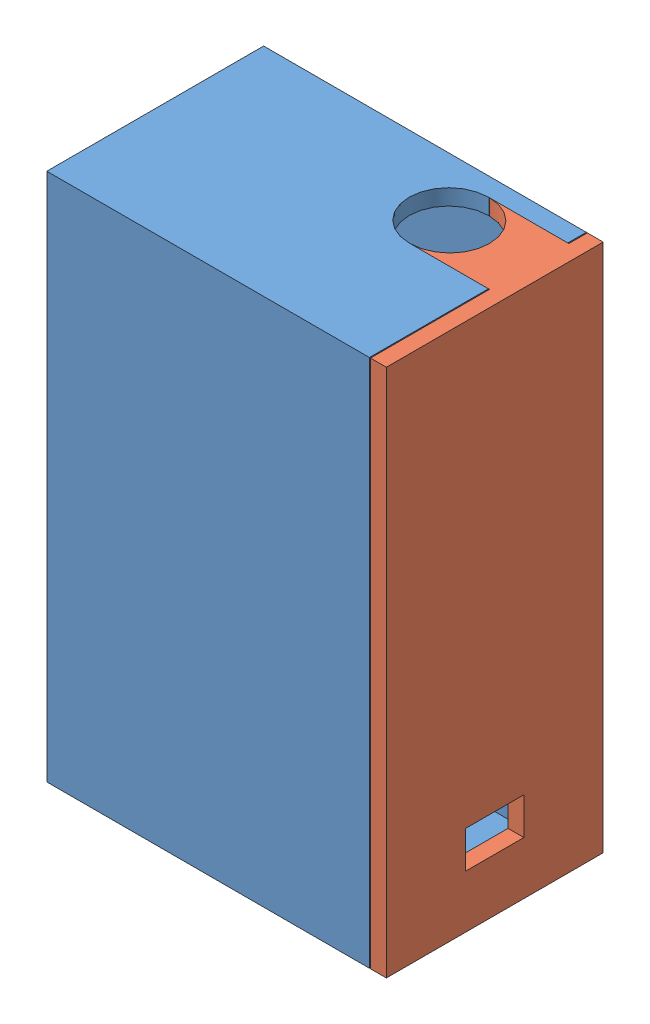
SolidWorks assembly IoT, configuration Défaut. Lengths in mm.
Overall size (64.2 100 41).
2 component instances, 2 part files, 4 mates.
Components (placement in the parent):
- IoT-1: IoT [Défaut] at (6.4877 -44.4058 100) size (61 100 41)
- IoT2-1: IoT2 [Défaut] at (40.183 5.5942 100) x (0 1 0) z (0 0 1) size (100 18 41)
Mates (geometry in assembly coordinates):
- Parallèle3: parallel anti-aligned: plane of IoT-1 through (36.9877 55.5942 120.5) normal (1 0 0); plane of IoT2-1 through (37.183 5.5942 100) normal (-1 0 0)
- Parallèle2: parallel anti-aligned: plane of IoT-1 through (21.9877 40.5942 98) normal (0 0 -1); plane of IoT2-1 through (22.183 55.5942 98) normal (0 0 1)
- Coïncidente2: coincident aligned: plane of IoT-1 through (-20.0123 52.5942 82.5) normal (0 -1 0); plane of IoT2-1 through (22.183 52.5942 83) normal (0 -1 0)
- Coïncidente3: coincident aligned: plane of IoT-1 through (-24.0123 55.5942 79.5) normal (0 0 -1); plane of IoT2-1 through (37.183 55.5942 79.5) normal (0 0 -1)
